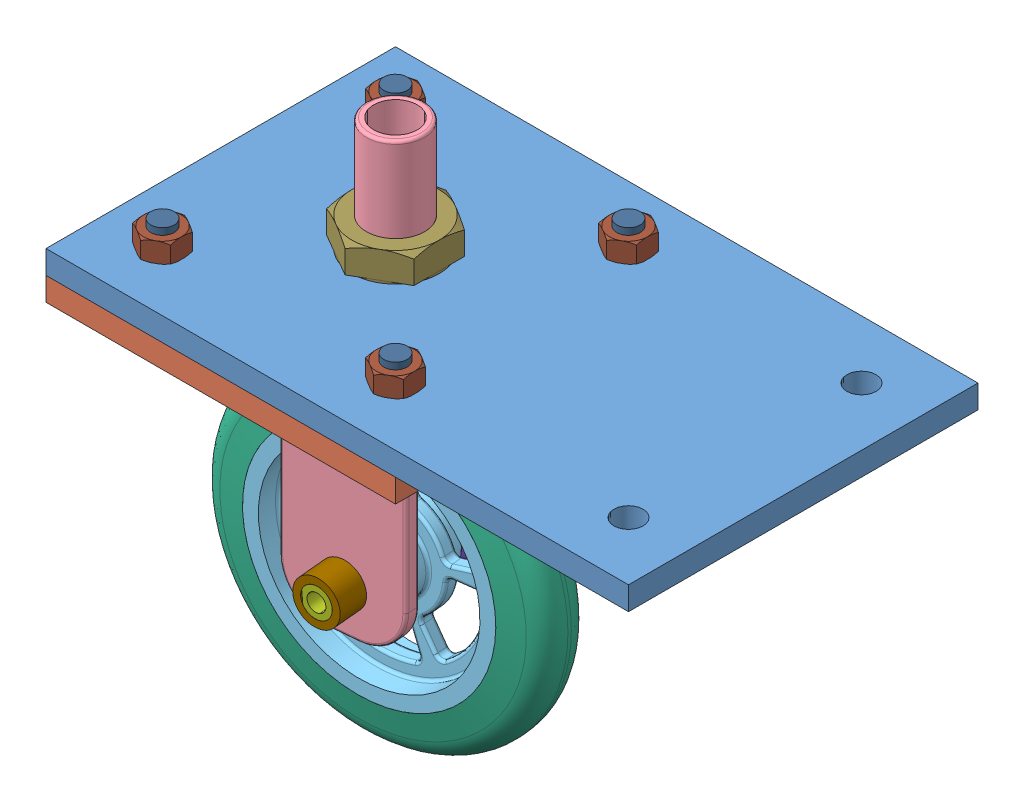
SolidWorks assembly final assembly-finished, configuration Default. Lengths in mm.
Overall size (207.49 193.03 120).
23 component instances, 13 part files, 24 mates.
Components (placement in the parent):
- Base.SLDPART.-2: Base.SLDPART. [Default] at (-67.2248 121.9152 -5.3212) size (200 8 120)
- Mount.SLDPART-1: Mount.SLDPART [Default] at (-67.2248 113.9152 -5.3212) x (0 0 -1) z (1 0 0) size (120 8 120)
- Bearing.SLDPART-1: Bearing.SLDPART [Default] at (-67.2248 113.9152 -5.3212) x (0.853471 0 0.521141) z (0 -1 0) size (30 30 5)
- Fork.SLDPART-1: Fork.SLDPART [Default] at (-67.2248 108.9152 -5.3212) x (-0.995838 0 0.091142) z (0.091142 0 0.995838) size (80 143 80)
- Wheel and Axel.2-1: Wheel and Axel.2 [Default] at (-33.3732 109.023 -31.9323) x (0.091142 0 0.995838) z (0.136834 -0.990515 -0.012523) size (60 115.31 115.31)
  - Wheel.SLDPART-1: Wheel.SLDPART [Default] at (23.415 45.1517 62.4965) size (20 80 80)
  - Tire.SLDPART-1: Tire.SLDPART [Default] at (23.415 45.1517 62.4965) x (1 0 0) z (0 -0.049481 0.998775) size (20 110 110)
  - Axel.SLDPART-1: Axel.SLDPART [Default] at (23.415 45.1517 62.4965) x (0 -0.050219 -0.998738) z (1 0 0) size (10 10 60)
  - Washer.SLDPART-1: Washer.SLDPART [Default] at (8.415 45.1517 62.4965) x (0 -0.153708 -0.988116) z (0 -0.988116 0.153708) size (25 5 25)
  - Washer.SLDPART-2: Washer.SLDPART [Default] at (38.415 45.1517 62.4965) x (0 0.906189 0.422872) z (0 -0.422872 0.906189) size (25 5 25)
- Collar.SLDPART-1: Collar.SLDPART [Default] at (-64.9463 40.9152 19.5747) x (0.087126 -0.996165 -0.007974) z (0.091142 0 0.995838) size (15 15 10)
- Collar.SLDPART-2: Collar.SLDPART [Default] at (-69.5034 40.9152 -30.2172) x (-0.087126 0.996165 0.007974) z (-0.091142 0 -0.995838) size (15 15 10)
- hex screw_am-8: hex screw_am [B18.6.7M - M8 x 1.25 x 25 Indented HHMS --25N] at (-107.2248 107.9152 -45.3212) x (0 1 0) z (0 0 1) size (31 15.01 13)
- hex nut style 1_am-4: hex nut style 1_am [B18.2.4.1M - Hex nut, Style 1,  M8 x 1.25 --D-N] at (-107.2248 129.8511 -45.3212) x (1 0 0) z (0 -1 0) size (13 15.01 6.8)
- hex nut style 1_am-5: hex nut style 1_am [B18.2.4.1M - Hex nut, Style 1,  M8 x 1.25 --D-N] at (-27.2248 129.8511 -45.3212) x (1 0 0) z (0 -1 0) size (13 15.01 6.8)
- hex nut style 1_am-6: hex nut style 1_am [B18.2.4.1M - Hex nut, Style 1,  M8 x 1.25 --D-N] at (-107.2248 129.8511 34.6788) x (1 0 0) z (0 -1 0) size (13 15.01 6.8)
- hex nut style 1_am-7: hex nut style 1_am [B18.2.4.1M - Hex nut, Style 1,  M8 x 1.25 --D-N] at (-27.2248 129.8511 34.6788) x (1 0 0) z (0 -1 0) size (13 15.01 6.8)
- hex screw_am-9: hex screw_am [B18.6.7M - M8 x 1.25 x 25 Indented HHMS --25N] at (-27.2248 107.9152 -45.3212) x (0 1 0) z (0 0 1) size (31 15.01 13)
- hex screw_am-10: hex screw_am [B18.6.7M - M8 x 1.25 x 25 Indented HHMS --25N] at (-107.2248 107.9152 34.6788) x (0 1 0) z (0 0 1) size (31 15.01 13)
- hex screw_am-11: hex screw_am [B18.6.7M - M8 x 1.25 x 25 Indented HHMS --25N] at (-27.2248 107.9152 34.6788) x (0 1 0) z (0 0 1) size (31 15.01 13)
- hex nut jam_am-3: hex nut jam_am [B18.2.4.5M - Hex jam nut,  M20 x 2.5 --W-N] at (-67.2248 139.9152 -5.3212) x (1 0 0) z (0 1 0) size (30 34.64 10)
- socket set screw flat point_am-11: socket set screw flat point_am [B18.3.6M - M3 x 0.5 x 4 Hex Socket Flat Pt. SS --N] at (-73.3784 40.1715 20.3465) x (0.992019 0.08749 -0.090793) z (-0.001118 0.726161 0.687524) size (4 3 3)
- socket set screw flat point_am-12: socket set screw flat point_am [B18.3.6M - M3 x 0.5 x 4 Hex Socket Flat Pt. SS --N] at (-77.9355 40.1715 -29.4454) x (0.992019 0.08749 -0.090793) z (0.097418 -0.98899 0.111394) size (4 3 3)
Mates (geometry in assembly coordinates):
- Coincident2: coincident anti-aligned: plane of Base.SLDPART.-2 through (-67.2248 121.9152 -5.3212) normal (0 -1 0); plane of Mount.SLDPART-1 through (-67.2248 121.9152 -5.3212) normal (0 1 0)
- Coincident3: coincident aligned: circle of Base.SLDPART.-2; circle of Mount.SLDPART-1
- Coincident4: coincident aligned: circle of Base.SLDPART.-2; circle of Mount.SLDPART-1
- Coincident5: coincident anti-aligned: plane of Mount.SLDPART-1 through (-67.2248 113.9152 -5.3212) normal (0 -1 0); plane of Bearing.SLDPART-1 through (-67.2248 113.9152 -5.3212) normal (0 1 0)
- Concentric1: concentric anti-aligned: circle of Mount.SLDPART-1; circle of Bearing.SLDPART-1
- Coincident8: coincident anti-aligned: plane of Bearing.SLDPART-1 through (-67.2248 108.9152 -5.3212) normal (0 -1 0); plane of Fork.SLDPART-1 through (-67.2248 108.9152 -5.3212) normal (0 1 0)
- Coincident9: coincident anti-aligned: circle of Bearing.SLDPART-1; circle of Fork.SLDPART-1
- Coincident13: coincident anti-aligned: plane of Fork.SLDPART-1 through (-65.8577 25.9152 9.6164) normal (-0.091142 0 -0.995838); plane of Wheel and Axel.2-1/Washer.SLDPART-2 through (-65.8577 40.9152 9.6164) normal (0.091142 0 0.995838)
- Concentric2: concentric aligned: cylinder of Fork.SLDPART-1 through (-62.1208 40.9152 50.4457) axis (-0.091142 0 -0.995838) radius 5; cylinder of Wheel and Axel.2-1/Axel.SLDPART-1 through (-64.4905 40.9152 24.5539) axis (-0.091142 0 -0.995838) radius 3
- Coincident15: coincident anti-aligned: plane of Fork.SLDPART-1 through (-69.0477 25.9152 -25.238) normal (-0.091142 0 -0.995838); plane of Collar.SLDPART-2 through (-69.0477 40.9152 -25.238) normal (0.091142 0 0.995838)
- Coincident18: coincident aligned: circle of Fork.SLDPART-1; circle of Collar.SLDPART-2
- Parallel4: parallel aligned: plane of Wheel and Axel.2-1/Axel.SLDPART-1 through (-67.2248 40.9152 -5.3212) normal (-0.087126 0.996165 0.007974); plane of Collar.SLDPART-2 through (-69.5034 40.9152 -30.2172) normal (-0.087126 0.996165 0.007974)
- Coincident20: coincident anti-aligned: plane of Fork.SLDPART-1 through (-65.402 25.9152 14.5955) normal (0.091142 0 0.995838); plane of Collar.SLDPART-1 through (-65.402 40.9152 14.5955) normal (-0.091142 0 -0.995838)
- Coincident21: coincident anti-aligned: circle of Fork.SLDPART-1; circle of Collar.SLDPART-1
- Parallel5: parallel anti-aligned: plane of Wheel and Axel.2-1/Axel.SLDPART-1 through (-67.2248 40.9152 -5.3212) normal (-0.087126 0.996165 0.007974); plane of Collar.SLDPART-1 through (-64.9463 40.9152 19.5747) normal (0.087126 -0.996165 -0.007974)
- Concentric6: concentric anti-aligned: cylinder of Mount.SLDPART-1 through (-107.2248 113.9152 -45.3212) axis (0 1 0) radius 5; cylinder of hex screw_am-8 through (-107.2248 82.5152 -45.3212) axis (0 -1 0) radius 4
- Coincident22: coincident anti-aligned: plane of Mount.SLDPART-1 through (-67.2248 113.9152 -5.3212) normal (0 -1 0); plane of hex screw_am-8 through (-111.2248 113.9152 -45.3212) normal (0 1 0)
- Concentric9: concentric aligned: cylinder of hex screw_am-8 through (-107.2248 82.5152 -45.3212) axis (0 -1 0) radius 4; cylinder of hex nut style 1_am-4 through (-107.2248 154.8886 -45.3212) axis (0 -1 0) radius 4
- Concentric12: concentric aligned: cylinder of Base.SLDPART.-2 through (-67.2248 119.9152 -5.3212) axis (0 1 0) radius 12.5; cylinder of hex nut jam_am-3 through (-67.2248 114.8777 -5.3212) axis (0 1 0) radius 10
- Coincident24: coincident anti-aligned: plane of Base.SLDPART.-2 through (-67.2248 129.9152 -5.3212) normal (0 1 0); plane of hex nut jam_am-3 through (-67.2248 129.9152 -22.6417) normal (0 -1 0)
- Coincident26: coincident anti-aligned: plane of Wheel and Axel.2-1/Axel.SLDPART-1 through (-70.0559 42.6926 15.0215) normal (-0.992019 -0.08749 0.090793); plane of socket set screw flat point_am-11 through (-69.5364 41.2034 19.2628) normal (0.992019 0.08749 -0.090793)
- Concentric164: concentric anti-aligned: cylinder of Collar.SLDPART-1 through (-72.3874 40.2589 20.2558) axis (0.992019 0.08749 -0.090793) radius 1.5; cylinder of socket set screw flat point_am-11 through (-85.9771 39.0604 21.4995) axis (-0.992019 -0.08749 0.090793) radius 1.5
- Coincident27: coincident anti-aligned: plane of Wheel and Axel.2-1/Axel.SLDPART-1 through (-73.7016 42.6926 -24.812) normal (-0.992019 -0.08749 0.090793); plane of socket set screw flat point_am-12 through (-73.8874 40.6408 -28.819) normal (0.992019 0.08749 -0.090793)
- Concentric165: concentric anti-aligned: cylinder of Collar.SLDPART-2 through (-76.9445 40.2589 -29.5361) axis (0.992019 0.08749 -0.090793) radius 1.5; cylinder of socket set screw flat point_am-12 through (-90.5342 39.0604 -28.2924) axis (-0.992019 -0.08749 0.090793) radius 1.5
